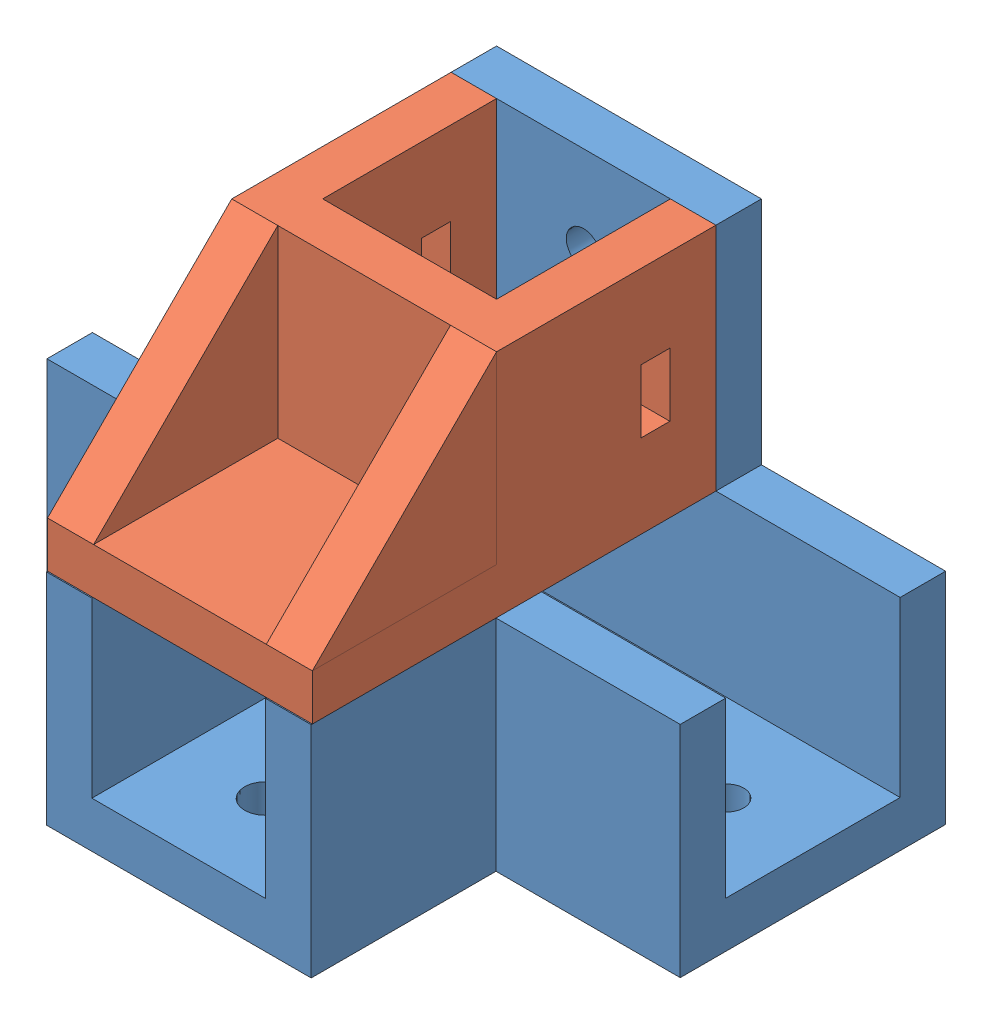
SolidWorks assembly 框架固定251, configuration 默认. Lengths in mm.
Overall size (55 39.05 39.1).
2 component instances, 2 part files, 3 mates.
Components (placement in the parent):
- 零件25-1: 零件25 [默认] at (8.6467 -17.4546 53.0648) size (55 39.05 39.1)
- 框架固定26-1: 框架固定26 [默认] at (1.9413 1.5954 47.3032) x (-1 0 0) z (0 0 -1) size (23 20 35.05)
Mates (geometry in assembly coordinates):
- 重合2: coincident: plane of assembly; plane of assembly; plane of 零件25-1 through (8.6467 1.5954 53.0648) normal (0 1 0); plane of 框架固定26-1 through (1.9413 1.5954 47.3032) normal (0 -1 0)
- 重合3: coincident: plane of assembly; plane of assembly; plane of 零件25-1 through (-16.2647 1.5954 39.4) normal (-1 0 0); plane of 框架固定26-1 through (-16.2647 5.5954 74.45) normal (-1 0 0)
- 重合4: coincident: plane of assembly; plane of assembly; plane of 零件25-1 through (-32.2647 1.5954 39.4) normal (0 0 1); plane of 框架固定26-1 through (2.7853 5.5954 39.4) normal (0 0 -1)
